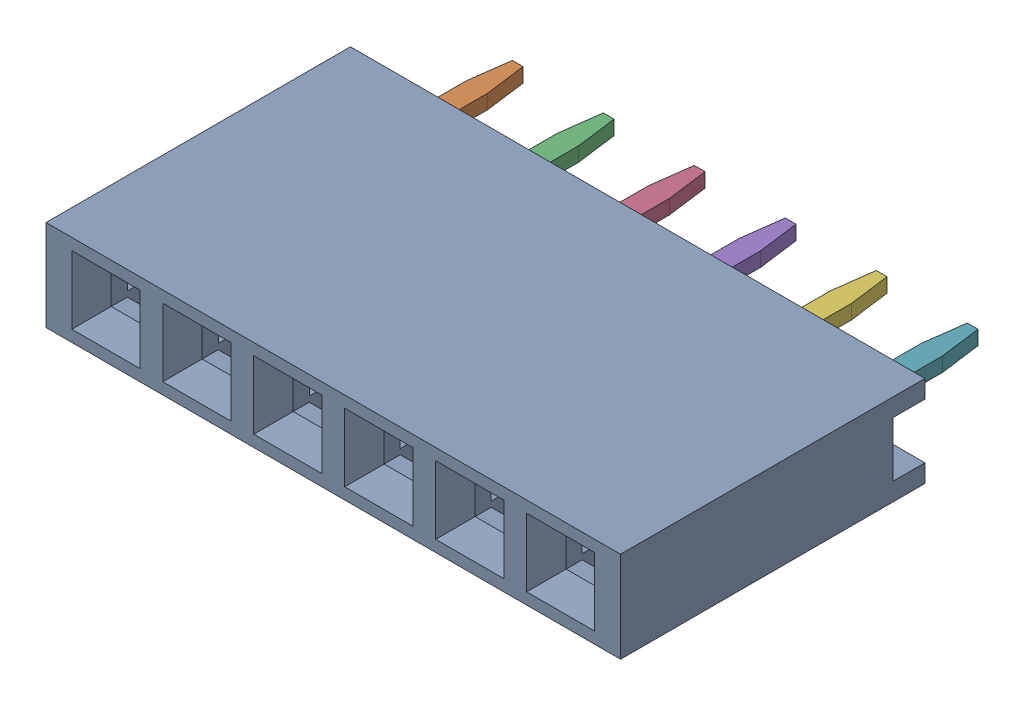
SolidWorks assembly DS1023-1x6SF11_1.step, configuration Default. Lengths in mm.
Overall size (16.04 2.54 11.5).
7 component instances, 2 part files, 0 mates.
Components (placement in the parent):
- body_3.step-32: body_3.step [Default] at origin size (16.04 2.54 8.5)
- contact_1.step-195: contact_1.step [Default] at origin size (2.3 0.4 9)
- contact_1.step-196: contact_1.step [Default] at (2.54 0 0) size (2.3 0.4 9)
- contact_1.step-199: contact_1.step [Default] at (5.08 0 0) size (2.3 0.4 9)
- contact_1.step-200: contact_1.step [Default] at (7.62 0 0) size (2.3 0.4 9)
- contact_1.step-201: contact_1.step [Default] at (10.16 0 0) size (2.3 0.4 9)
- contact_1.step-202: contact_1.step [Default] at (12.7 0 0) size (2.3 0.4 9)
